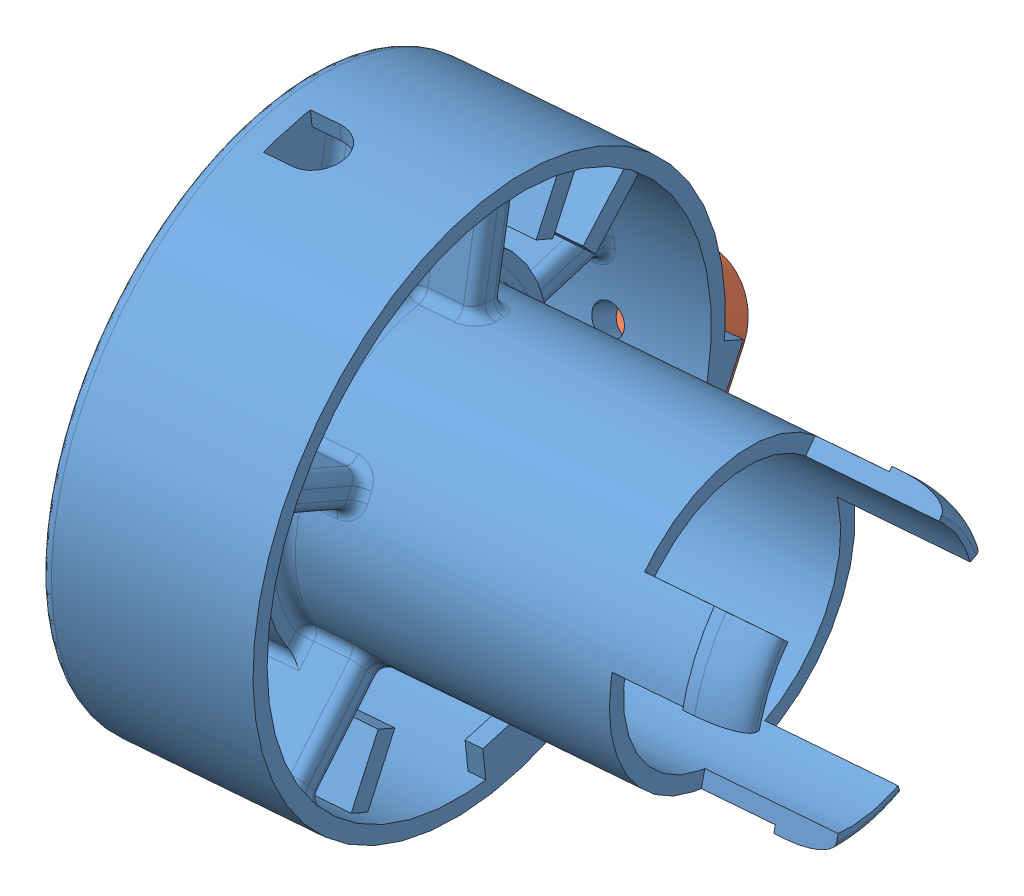
SolidWorks assembly CycloneDisplayAssem, configuration Default. Lengths in mm.
Overall size (56.4 68.48 72.48).
2 component instances, 2 part files, 3 mates.
Components (placement in the parent):
- DisplayMainBody-1: DisplayMainBody [Default] at (29.9069 -19.1819 -33.112) x (0.993314 -0.026739 -0.112301) z (0.026579 -0.893694 0.447889) size (49.77 50.16 50)
- DisplaySensorTab-1: DisplaySensorTab [Default] at (24.6836 -26.0287 -64.3253) x (0.026579 -0.893694 0.447889) z (-0.993314 0.026739 0.112301) size (26 3 10)
Mates (geometry in assembly coordinates):
- Distance1: distance = 3.175 mm: plane of DisplaySensorTab-1 through (25.0207 -24.685 -61.6643) normal (0.112339 0.447879 0.887009); plane of DisplayMainBody-1 through (27.0799 -30.4527 -55.4334) normal (-0.112339 -0.447879 -0.887009)
- Concentric1: concentric: cylinder of DisplayMainBody-1 through (31.4381 -15.094 -7.1844) axis (-0.112339 -0.447879 -0.887009) radius 1.375; cylinder of DisplaySensorTab-1 through (25.4459 -38.9842 -54.498) axis (-0.112339 -0.447879 -0.887009) radius 1.625
- Concentric2: concentric: cylinder of DisplayMainBody-1 through (31.0129 -0.7948 -14.3506) axis (-0.112339 -0.447879 -0.887009) radius 1.375; cylinder of DisplaySensorTab-1 through (25.0207 -24.685 -61.6643) axis (-0.112339 -0.447879 -0.887009) radius 1.625
